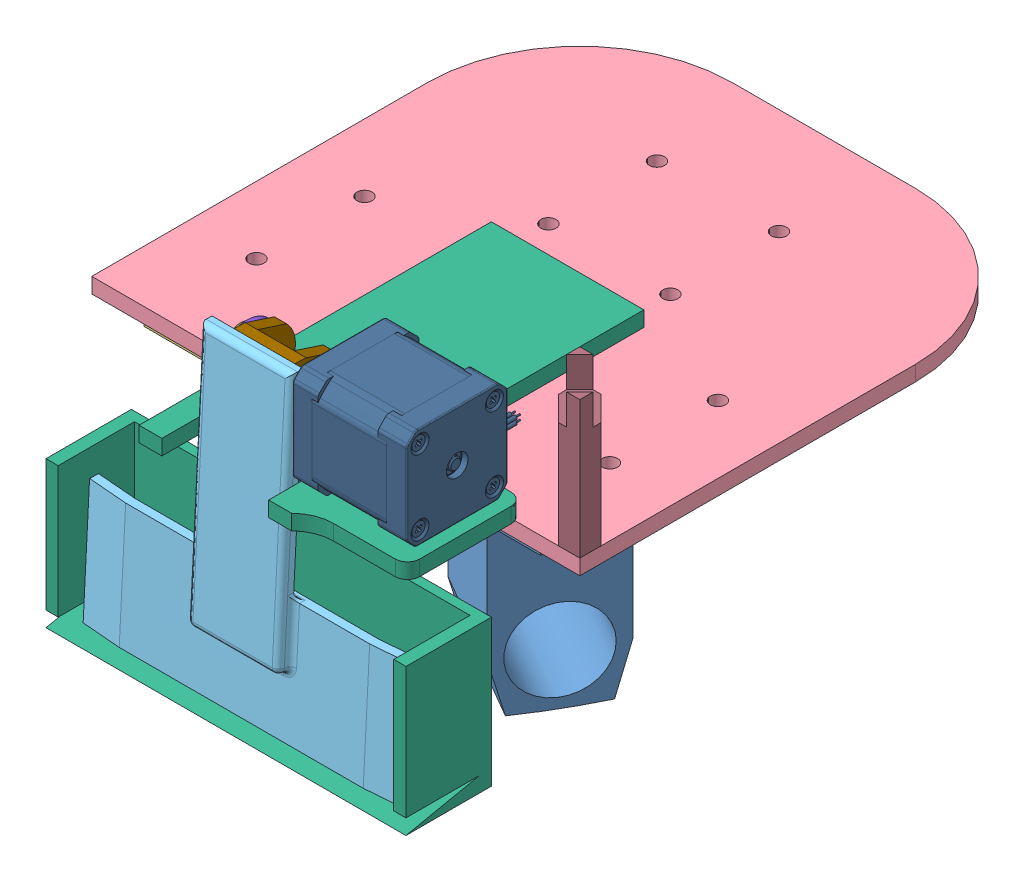
SolidWorks assembly Milestone2_scooper_test, configuration Default. Lengths in mm.
Overall size (219.72 147.64 253.37).
14 component instances, 13 part files, 16 mates.
Components (placement in the parent):
- 12V Motor Support - Left-1: 12V Motor Support - Left [Default] at (103.4795 4.8457 33.7132) x (0.866025 0 0.5) z (-0.5 0 0.866025) size (86.05 76.69 86.05)
- 12V Motor Support - Rear-1: 12V Motor Support - Rear [Default] at (54.0063 4.8457 -79.8948) x (0 0 -1) z (1 0 0) size (62.99 76.31 63.5)
- 12V Motor Support -Right-1: 12V Motor Support -Right [Default] at (1.3037 4.8457 33.7132) x (0.866025 0 -0.5) z (0.5 0 0.866025) size (86.05 76.69 86.05)
- Acrylic Plate (square 12 inch) cut version v2 thinner-1: Acrylic Plate (square 12 inch) cut version v2 thinner [Default] at (54.0063 60.2177 -32.145) size (203.2 6.35 203.2)
- ScoopClawAssembly_m2-1: ScoopClawAssembly_m2 [Default] at (-90.601 37.6142 27.2562) size (149.86 138.94 146.69)
  - Scooper_m2-1: Scooper_m2 [Default] at (144.6073 -34.5841 76.4289) x (1 0 0) z (0 0.052593 0.998616) size (134.49 132.08 10.33)
  - Scooper_Base_m2-1: Scooper_Base_m2 [Default] at (144.6073 -61.534 72.0438) size (149.86 96.84 146.69)
  - HC-SR04-UltrasonicSensor v7-2: HC-SR04-UltrasonicSensor v7 [Default] at (144.5683 -48.834 47.0588) x (-1 0 0) z (0 0 1) size (45.45 26.2 17.79)
  - Hinge_Part1_base_side-1: Hinge_Part1_base_side [Default] at (144.6073 35.3035 61.4739) size (35.56 29.45 25.4)
  - Hinge_Part2__scoop_sdie-1: Hinge_Part2__scoop_sdie [Default] at (144.6073 56.9297 75.4245) x (1 0 0) z (0 0.998616 -0.052593) size (25.4 24.06 25.4)
  - 17HM19-2004S-1: 17HM19-2004S [По умолчанию] at (214.4273 69.2601 59.7763) x (0 -0.999984 0.005702) z (0 -0.005702 -0.999984) size (42.19 71.6 51.3)
  - Hinge_NEMA17_m2-1: Hinge_NEMA17_m2 [Default] at (162.3873 69.2573 59.755) x (0 -0.999973 0.007334) z (-1 0 0) size (12.7 12.7 38.1)
  - Hinge_Cap_m2-1: Hinge_Cap_m2 [Default] at (126.8273 56.195 61.4739) x (0 1 0) z (0 0 1) size (12.7 2.54 12.7)
- corner_support-1: corner_support [Default] at (146.0813 66.5677 59.93) x (0 0 1) z (-1 0 0) size (19.05 57.15 19.05)
Mates (geometry in assembly coordinates):
- Coincident1: coincident: plane of 12V Motor Support - Rear-1 through (54.0063 60.2177 -79.8948) normal (0 1 0); plane of Acrylic Plate (square 12 inch) cut version v2 thinner-1 through (54.0063 60.2177 -32.145) normal (0 -1 0)
- Coincident5: coincident: plane of 12V Motor Support - Left-1 through (103.4795 60.2177 33.7132) normal (0 1 0); plane of Acrylic Plate (square 12 inch) cut version v2 thinner-1 through (54.0063 60.2177 -32.145) normal (0 -1 0)
- Parallel4: parallel: plane of 12V Motor Support - Left-1 through (71.9835 60.2177 65.2092) normal (-1 0 0); plane of Acrylic Plate (square 12 inch) cut version v2 thinner-1 through (-47.5937 66.5677 69.455) normal (-1 0 0)
- Coincident10: coincident: plane of 12V Motor Support -Right-1 through (1.3037 60.2177 33.7132) normal (0 1 0); plane of Acrylic Plate (square 12 inch) cut version v2 thinner-1 through (54.0063 60.2177 -32.145) normal (0 -1 0)
- Parallel5: parallel: plane of 12V Motor Support -Right-1 through (-30.1923 60.2177 65.2092) normal (-1 0 0); plane of Acrylic Plate (square 12 inch) cut version v2 thinner-1 through (-47.5937 66.5677 69.455) normal (-1 0 0)
- Distance1: distance = 69.85 mm: plane of 12V Motor Support - Rear-1 through (22.2563 60.2177 -111.3908) normal (-1 0 0); plane of Acrylic Plate (square 12 inch) cut version v2 thinner-1 through (-47.5937 66.5677 69.455) normal (-1 0 0)
- Distance4: distance = 9.05 mm: line of 12V Motor Support -Right-1 through (32.7997 55.1377 65.2092) axis (0 0 -1); line of Acrylic Plate (square 12 inch) cut version v2 thinner-1 through (25.31 60.2177 28.8207) axis (0 0 -1)
- Distance5: distance = 19.05 mm: line of 12V Motor Support -Right-1 through (32.7997 55.1377 2.2172) axis (-1 0 0); line of Acrylic Plate (square 12 inch) cut version v2 thinner-1 through (-19.6537 60.2177 -16.143) axis (1 0 0)
- Distance7: distance = 9.05 mm: line of 12V Motor Support - Left-1 through (134.9755 55.1377 65.2092) axis (0 0 -1); line of Acrylic Plate (square 12 inch) cut version v2 thinner-1 through (127.4858 60.2177 28.8207) axis (0 0 -1)
- Distance8: distance = 19.05 mm: line of 12V Motor Support - Left-1 through (134.9755 55.1377 2.2172) axis (-1 0 0); line of Acrylic Plate (square 12 inch) cut version v2 thinner-1 through (82.5221 60.2177 -16.143) axis (1 0 0)
- Coincident22: coincident: plane of Acrylic Plate (square 12 inch) cut version v2 thinner-1 through (54.0063 66.5677 -32.145) normal (0 1 0); plane of ScoopClawAssembly_m2-1/Scooper_Base_m2-1 through (54.0063 66.5677 99.3) normal (0 -1 0)
- Distance9: distance = 69.85 mm: plane of ScoopClawAssembly_m2-1/Scooper_Base_m2-1 through (85.7563 15.7677 74.535) normal (1 0 0); plane of Acrylic Plate (square 12 inch) cut version v2 thinner-1 through (155.6063 66.5677 69.455) normal (1 0 0)
- Coincident24: coincident: line of Acrylic Plate (square 12 inch) cut version v2 thinner-1 through (-47.5937 66.5677 69.455) axis (1 0 0); line of ScoopClawAssembly_m2-1/Scooper_Base_m2-1 through (83.2163 66.5677 69.455) axis (-1 0 0)
- Coincident25: coincident: plane of Acrylic Plate (square 12 inch) cut version v2 thinner-1 through (155.6063 66.5677 69.455) normal (1 0 0); plane of corner_support-1 through (155.6063 111.0177 50.405) normal (1 0 0)
- Coincident26: coincident: plane of Acrylic Plate (square 12 inch) cut version v2 thinner-1 through (54.0063 66.5677 -32.145) normal (0 1 0); plane of corner_support-1 through (146.0813 66.5677 59.93) normal (0 -1 0)
- Coincident27: coincident: plane of Acrylic Plate (square 12 inch) cut version v2 thinner-1 through (-47.5937 66.5677 69.455) normal (0 0 1); plane of corner_support-1 through (136.5563 111.0177 69.455) normal (0 0 1)
